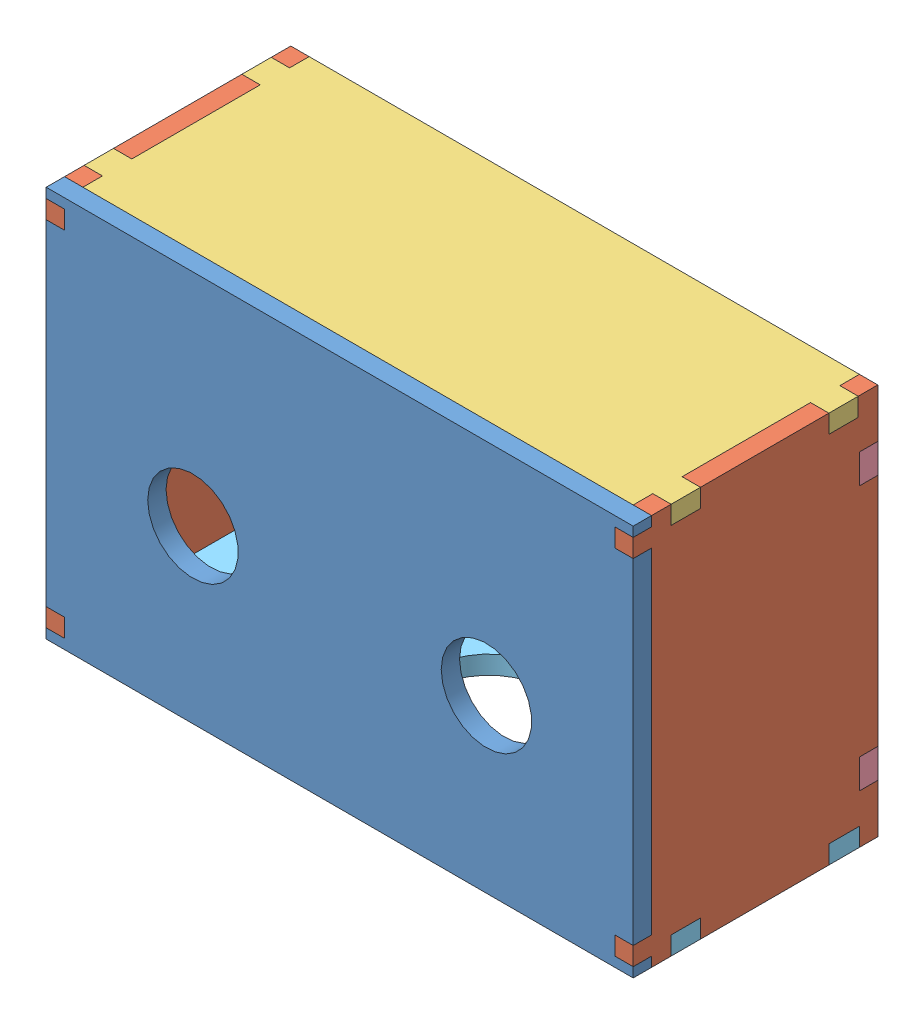
SolidWorks assembly Assem1Box, configuration Default. Lengths in mm.
Overall size (152.4 101.6 63.5).
6 component instances, 5 part files, 23 mates.
Components (placement in the parent):
- Part1^Assem1Box-1: Part1^Assem1Box [Default] at origin size (152.4 101.6 4.76) (virtual)
- Part2-1: Part2 [Default] at (147.6375 0 0) x (0 0 -1) z (1 0 0) size (63.5 101.6 4.76)
- Part2-2: Part2 [Default] at (4.7625 -101.6 0) x (0 0 -1) z (-1 0 0) size (63.5 101.6 4.76)
- Part3-1: Part3 [Default] at (4.7625 -4.7625 0) x (0 0 1) z (0 1 0) size (63.5 152.4 4.76)
- Part4^Assem1Box-1: Part4^Assem1Box [Default] at (147.6375 0 -53.975) x (-1 0 0) z (0 0 -1) size (152.4 92.08 4.76) (virtual)
- Part5^Assem1Box-1: Part5^Assem1Box [Default] at (4.7625 -96.8375 0) x (0 0 -1) z (0 -1 0) size (58.74 152.4 4.76) (virtual)
Mates (geometry in assembly coordinates):
- InPlace1: in place: plane of Part1^Assem1Box-1 through (0 0 0) normal (0 0 1); moOrthogonalPlaneRef_w of Part1^Assem1Box-1 through (0 0 0) normal (0 1 0); plane of Part1^Assem1Box-1 through (0 0 0) normal (1 0 0); unknown of Part1^Assem1Box-1
- Coincident1: coincident aligned: 
- Coincident2: coincident aligned: plane of Part1^Assem1-1 through (0 0 0) normal (0 1 0)
- Coincident3: coincident anti-aligned: plane of Part1^Assem1-1 through (0 0 0) normal (1 0 0)
- InPlace2: in place: plane of Part1^Assem1Box-1 through (142.24 0 4.7625) normal (1 0 0); plane of ? through (142.24 0 0) normal (1 0 0); plane of Part1^Assem1Box-1 through (142.24 0 4.7625) normal (1 0 0); plane of ? through (142.24 0 0) normal (0 1 0); plane of Part1^Assem1Box-1 through (142.24 0 4.7625) normal (1 0 0); plane of ? through (142.24 0 0) normal (0 0 -1); plane of Part1^Assem1Box-1 through (147.6375 0 4.7625) normal (1 0 0); unknown of Part2-1
- Coincident4: coincident aligned: plane of ?; plane of ?
- Coincident5: coincident aligned: moOrthogonalPlaneRef_w of Part1^Assem1-1 through (147.6375 0 0) normal (0 1 0); plane of Part2^Assem1Box-1 through (147.6375 0 0) normal (0 1 0)
- Coincident6: coincident anti-aligned: moOrthogonalPlaneRef_w of Part1^Assem1-1 through (147.6375 0 0) normal (0 0 1); plane of Part2^Assem1Box-1 through (147.6375 0 0) normal (0 0 -1)
- Coincident7: coincident anti-aligned: plane of Part1^Assem1Box-1 through (4.7625 0 4.7625) normal (-1 0 0); plane of Part2-2 through (4.7625 -101.6 0) normal (1 0 0)
- Coincident9: coincident anti-aligned: plane of Part1^Assem1Box-1 through (0 -2.54 4.7625) normal (0 -1 0); plane of Part2-2 through (0 -2.54 0) normal (0 1 0)
- Coincident10: coincident anti-aligned: plane of Part1^Assem1Box-1 through (0 0 0) normal (0 0 -1); plane of Part2-2 through (0 -101.6 0) normal (0 0 1)
- InPlace3: in place: plane of Part2-2 through (0 -4.7625 0) normal (0 1 0); plane of ? through (0 -4.7625 0) normal (0 1 0); plane of Part2-2 through (0 -4.7625 0) normal (0 1 0); plane of ? through (0 -4.7625 0) normal (0 0 -1); plane of Part2-2 through (0 -4.7625 0) normal (0 1 0); plane of ? through (0 -4.7625 0) normal (1 0 0); plane of Part2-2 through (0 -4.7625 0) normal (0 1 0); unknown of Part3-1
- Coincident11: coincident aligned: plane of ?; plane of ?
- Coincident12: coincident aligned: moOrthogonalPlaneRef_w of Part2-2 through (4.7625 -4.7625 0) normal (1 0 0); plane of Part3^Assem1Box-1 through (4.7625 -4.7625 0) normal (1 0 0)
- Coincident13: coincident anti-aligned: moOrthogonalPlaneRef_w of Part2-2 through (4.7625 -4.7625 0) normal (0 0 -1); plane of Part3^Assem1Box-1 through (4.7625 -4.7625 0) normal (0 0 1)
- InPlace4: in place: plane of Part2-1 through (152.4 0 -53.975) normal (0 0 -1); plane of ? through (0 0 -53.975) normal (0 0 -1); plane of Part2-1 through (152.4 0 -53.975) normal (0 0 -1); plane of ? through (0 0 -53.975) normal (0 1 0); plane of Part2-1 through (152.4 0 -53.975) normal (0 0 -1); plane of ? through (0 0 -53.975) normal (-1 0 0); plane of Part2-1 through (152.4 0 -53.975) normal (0 0 -1); unknown of Part4^Assem1Box-1
- Coincident14: coincident aligned: plane of ?; plane of ?
- Coincident15: coincident aligned: moOrthogonalPlaneRef_w of Part2-1 through (147.6375 0 -53.975) normal (0 1 0); plane of Part4^Assem1Box-1 through (147.6375 0 -53.975) normal (0 1 0)
- Coincident16: coincident anti-aligned: moOrthogonalPlaneRef_w of Part2-1 through (147.6375 0 -53.975) normal (1 0 0); plane of Part4^Assem1Box-1 through (147.6375 0 -53.975) normal (-1 0 0)
- InPlace5: in place: plane of Part2-2 through (0 -96.8375 0) normal (0 -1 0); plane of ? through (0 -96.8375 0) normal (0 -1 0); plane of Part2-2 through (0 -96.8375 0) normal (0 -1 0); plane of ? through (0 -96.8375 0) normal (0 0 -1); plane of Part2-2 through (0 -96.8375 0) normal (0 -1 0); plane of ? through (0 -96.8375 0) normal (-1 0 0); plane of Part2-2 through (0 -96.8375 0) normal (0 -1 0); unknown of Part5^Assem1Box-1
- Coincident17: coincident aligned: plane of ?; plane of ?
- Coincident18: coincident aligned: moOrthogonalPlaneRef_w of Part2-2 through (4.7625 -96.8375 0) normal (1 0 0); plane of Part5^Assem1Box-1 through (4.7625 -96.8375 0) normal (1 0 0)
- Coincident19: coincident anti-aligned: moOrthogonalPlaneRef_w of Part2-2 through (4.7625 -96.8375 0) normal (0 0 1); plane of Part5^Assem1Box-1 through (4.7625 -96.8375 0) normal (0 0 -1)
